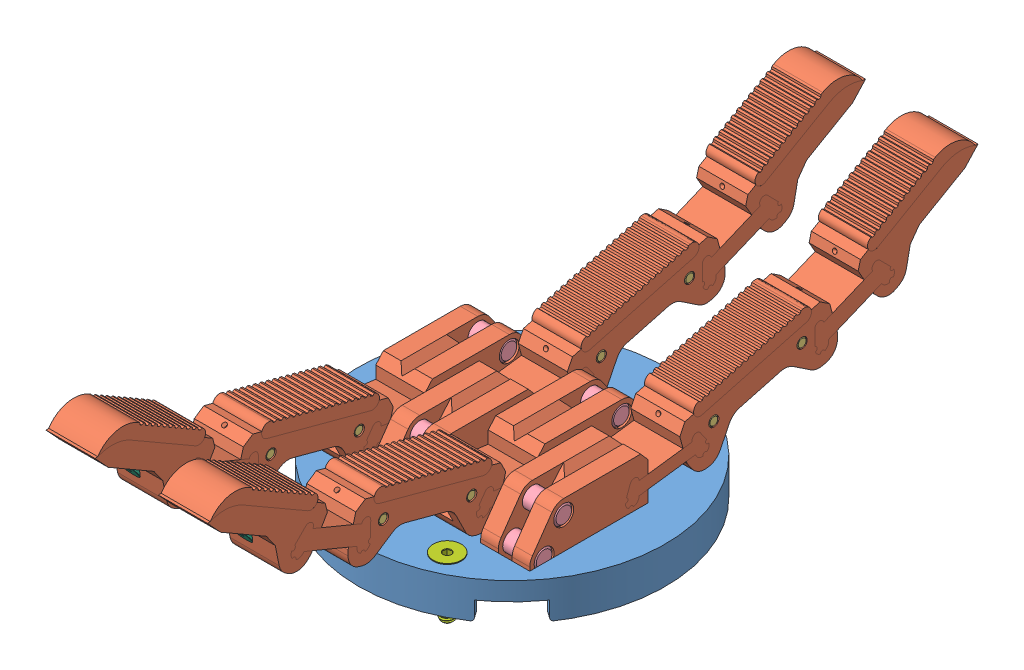
SolidWorks assembly block_top_ff_t, configuration Default. Lengths in mm.
Overall size (100 71.86 234.28).
37 component instances, 7 part files, 20 mates.
Components (placement in the parent):
- a1_f_t-1: a1_f_t [Default] at origin size (100 12.06 100)
- block_finger_ff_t-1: block_finger_ff_t [Default] at (-9.0917 8.2832 -0.0007) size (19 58.78 150.92)
  - finger_ff_t-1: finger_ff_t [Default] at origin size (19 58.78 150.92)
  - 98381A472 D1-8 L5-8-1: 98381A472 D1-8 L5-8 [98381A472] at (0.0625 5.5634 -30.2193) size (15.88 3.17 3.17)
  - 98381A472 D1-8 L5-8-2: 98381A472 D1-8 L5-8 [98381A472] at (0.0625 13.2775 -59.0086) size (15.88 3.17 3.17)
  - 98381A539 D1-4 L5-8-1: 98381A539 D1-4 L5-8 [98381A539] at (0.0625 3.5418 18.7031) size (15.88 6.35 6.35)
  - 98381A539 D1-4 L5-8-2: 98381A539 D1-4 L5-8 [98381A539] at (0.0625 -5.6082 25.11) size (15.88 6.35 6.35)
  - 93365A120 4-40 insert-1: 93365A120 4-40 insert [93365A120] at (0 25.5032 -95.7226) x (1 0 0) z (0 0.812659 -0.582739) size (4.37 3.82 4.37)
  - 91253A106 4-40 L1-4 countersunk-1: 91253A106 4-40 L1-4 countersunk [91253A106] at (0 24.2671 -97.4464) x (0.996599 0.066964 -0.048019) z (0 -0.582739 -0.812659) size (6.48 6.48 6.63)
- block_finger_ff_t-2: block_finger_ff_t [Default] at (27.575 8.2832 -0.0007) size (19 58.78 150.92)
  - finger_ff_t-1: finger_ff_t [Default] at origin size (19 58.78 150.92)
  - 98381A472 D1-8 L5-8-1: 98381A472 D1-8 L5-8 [98381A472] at (0.0625 5.5634 -30.2193) size (15.88 3.17 3.17)
  - 98381A472 D1-8 L5-8-2: 98381A472 D1-8 L5-8 [98381A472] at (0.0625 13.2775 -59.0086) size (15.88 3.17 3.17)
  - 98381A539 D1-4 L5-8-1: 98381A539 D1-4 L5-8 [98381A539] at (0.0625 3.5418 18.7031) size (15.88 6.35 6.35)
  - 98381A539 D1-4 L5-8-2: 98381A539 D1-4 L5-8 [98381A539] at (0.0625 -5.6082 25.11) size (15.88 6.35 6.35)
  - 93365A120 4-40 insert-1: 93365A120 4-40 insert [93365A120] at (0 25.5032 -95.7226) x (1 0 0) z (0 0.812659 -0.582739) size (4.37 3.82 4.37)
  - 91253A106 4-40 L1-4 countersunk-1: 91253A106 4-40 L1-4 countersunk [91253A106] at (0 24.2671 -97.4464) x (0.996599 0.066964 -0.048019) z (0 -0.582739 -0.812659) size (6.48 6.48 6.63)
- block_finger_ff_t-3: block_finger_ff_t [Default] at (-27.575 8.2832 0.0007) x (-1 0 0) z (0 0 -1) size (19 58.78 150.92)
  - finger_ff_t-1: finger_ff_t [Default] at origin size (19 58.78 150.92)
  - 98381A472 D1-8 L5-8-1: 98381A472 D1-8 L5-8 [98381A472] at (0.0625 5.5634 -30.2193) size (15.88 3.17 3.17)
  - 98381A472 D1-8 L5-8-2: 98381A472 D1-8 L5-8 [98381A472] at (0.0625 13.2775 -59.0086) size (15.88 3.17 3.17)
  - 98381A539 D1-4 L5-8-1: 98381A539 D1-4 L5-8 [98381A539] at (0.0625 3.5418 18.7031) size (15.88 6.35 6.35)
  - 98381A539 D1-4 L5-8-2: 98381A539 D1-4 L5-8 [98381A539] at (0.0625 -5.6082 25.11) size (15.88 6.35 6.35)
  - 93365A120 4-40 insert-1: 93365A120 4-40 insert [93365A120] at (0 25.5032 -95.7226) x (1 0 0) z (0 0.812659 -0.582739) size (4.37 3.82 4.37)
  - 91253A106 4-40 L1-4 countersunk-1: 91253A106 4-40 L1-4 countersunk [91253A106] at (0 24.2671 -97.4464) x (0.996599 0.066964 -0.048019) z (0 -0.582739 -0.812659) size (6.48 6.48 6.63)
- block_finger_ff_t-4: block_finger_ff_t [Default] at (9.0917 8.2832 0.0007) x (-1 0 0) z (0 0 -1) size (19 58.78 150.92)
  - finger_ff_t-1: finger_ff_t [Default] at origin size (19 58.78 150.92)
  - 98381A472 D1-8 L5-8-1: 98381A472 D1-8 L5-8 [98381A472] at (0.0625 5.5634 -30.2193) size (15.88 3.17 3.17)
  - 98381A472 D1-8 L5-8-2: 98381A472 D1-8 L5-8 [98381A472] at (0.0625 13.2775 -59.0086) size (15.88 3.17 3.17)
  - 98381A539 D1-4 L5-8-1: 98381A539 D1-4 L5-8 [98381A539] at (0.0625 3.5418 18.7031) size (15.88 6.35 6.35)
  - 98381A539 D1-4 L5-8-2: 98381A539 D1-4 L5-8 [98381A539] at (0.0625 -5.6082 25.11) size (15.88 6.35 6.35)
  - 93365A120 4-40 insert-1: 93365A120 4-40 insert [93365A120] at (0 25.5032 -95.7226) x (1 0 0) z (0 0.812659 -0.582739) size (4.37 3.82 4.37)
  - 91253A106 4-40 L1-4 countersunk-1: 91253A106 4-40 L1-4 countersunk [91253A106] at (0 24.2671 -97.4464) x (0.996599 0.066964 -0.048019) z (0 -0.582739 -0.812659) size (6.48 6.48 6.63)
- 92210A197 8-32 L3-4 countersunk-1: 92210A197 8-32 L3-4 countersunk [92210A197] at (17.0093 1.7845 38.128) x (-0.285144 0 -0.958485) z (0 1 0) size (9.12 9.12 19.5)
- 92210A197 8-32 L3-4 countersunk-2: 92210A197 8-32 L3-4 countersunk [92210A197] at (17.0093 1.7845 -38.128) x (1 0 0) z (0 1 0) size (9.12 9.12 19.5)
- 92210A197 8-32 L3-4 countersunk-3: 92210A197 8-32 L3-4 countersunk [92210A197] at (-17.0093 1.7845 38.128) x (1 0 0) z (0 1 0) size (9.12 9.12 19.5)
- 92210A197 8-32 L3-4 countersunk-4: 92210A197 8-32 L3-4 countersunk [92210A197] at (-17.0093 1.7845 -38.128) x (1 0 0) z (0 1 0) size (9.12 9.12 19.5)
Mates (geometry in assembly coordinates):
- Coincident1: coincident anti-aligned: plane of a1_f_t-1 through (-1.0917 1.5 29.7843) normal (-1 0 0); plane of block_finger_ff_t-1/finger_ff_t-1 through (-1.0917 8.2832 -0.0007) normal (1 0 0)
- Coincident2: coincident anti-aligned: plane of a1_f_t-1 through (-1.0917 1.5 29.7843) normal (0 0 -1); plane of block_finger_ff_t-1/finger_ff_t-1 through (-1.0917 16.5 29.7843) normal (0 0 1)
- Coincident3: coincident anti-aligned: plane of a1_f_t-1 through (0 -1.5 0) normal (0 -1 0); plane of block_finger_ff_t-1/finger_ff_t-1 through (-9.0917 -1.5 -0.0007) normal (0 1 0)
- Coincident4: coincident anti-aligned: plane of a1_f_t-1 through (35.575 1.5 29.7843) normal (-1 0 0); plane of block_finger_ff_t-2/finger_ff_t-1 through (35.575 8.2832 -0.0007) normal (1 0 0)
- Coincident5: coincident anti-aligned: plane of a1_f_t-1 through (0 -1.5 0) normal (0 -1 0); plane of block_finger_ff_t-2/finger_ff_t-1 through (27.575 -1.5 -0.0007) normal (0 1 0)
- Coincident6: coincident anti-aligned: plane of a1_f_t-1 through (35.575 1.5 29.7843) normal (0 0 -1); plane of block_finger_ff_t-2/finger_ff_t-1 through (35.575 16.5 29.7843) normal (0 0 1)
- Coincident7: coincident anti-aligned: plane of a1_f_t-1 through (1.0917 1.5 8.7858) normal (1 0 0); plane of block_finger_ff_t-4/finger_ff_t-1 through (1.0917 8.2832 0.0007) normal (-1 0 0)
- Coincident8: coincident anti-aligned: plane of a1_f_t-1 through (17.2417 1.5 -29.7843) normal (0 0 1); plane of block_finger_ff_t-4/finger_ff_t-1 through (1.0917 16.5 -29.7843) normal (0 0 -1)
- Coincident9: coincident anti-aligned: plane of a1_f_t-1 through (0 -1.5 0) normal (0 -1 0); plane of block_finger_ff_t-4/finger_ff_t-1 through (9.0917 -1.5 0.0007) normal (0 1 0)
- Coincident10: coincident anti-aligned: plane of a1_f_t-1 through (-35.575 1.5 8.7858) normal (1 0 0); plane of block_finger_ff_t-3/finger_ff_t-1 through (-35.575 8.2832 0.0007) normal (-1 0 0)
- Coincident11: coincident anti-aligned: plane of a1_f_t-1 through (-19.425 1.5 -29.7843) normal (0 0 1); plane of block_finger_ff_t-3/finger_ff_t-1 through (-35.575 16.5 -29.7843) normal (0 0 -1)
- Coincident12: coincident anti-aligned: plane of a1_f_t-1 through (0 -1.5 0) normal (0 -1 0); plane of block_finger_ff_t-3/finger_ff_t-1 through (-27.575 -1.5 0.0007) normal (0 1 0)
- Concentric1: concentric aligned: cylinder of a1_f_t-1 through (17.0093 1.5 38.128) axis (0 1 0) radius 2.2479; circle of 92210A197 8-32 L3-4 countersunk-1
- Coincident13: coincident aligned: cone of a1_f_t-1 through (17.0093 1.5 38.128) axis (0 -1 0); cone of 92210A197 8-32 L3-4 countersunk-1 through (17.0093 -1.0603 38.128) axis (0 -1 0)
- Concentric3: concentric aligned: cylinder of a1_f_t-1 through (17.0093 1.5 -38.128) axis (0 1 0) radius 2.2479; circle of 92210A197 8-32 L3-4 countersunk-2
- Coincident14: coincident aligned: cone of a1_f_t-1 through (17.0093 1.5 -38.128) axis (0 -1 0); cone of 92210A197 8-32 L3-4 countersunk-2 through (17.0093 -1.0603 -38.128) axis (0 -1 0)
- Concentric5: concentric aligned: cylinder of a1_f_t-1 through (-17.0093 1.5 -38.128) axis (0 1 0) radius 2.2479; circle of 92210A197 8-32 L3-4 countersunk-4
- Coincident15: coincident aligned: cone of a1_f_t-1 through (-17.0093 1.5 -38.128) axis (0 -1 0); cone of 92210A197 8-32 L3-4 countersunk-4 through (-17.0093 -1.0603 -38.128) axis (0 -1 0)
- Concentric7: concentric aligned: cylinder of a1_f_t-1 through (-17.0093 1.5 38.128) axis (0 1 0) radius 2.2479; circle of 92210A197 8-32 L3-4 countersunk-3
- Coincident16: coincident aligned: cone of a1_f_t-1 through (-17.0093 1.5 38.128) axis (0 -1 0); cone of 92210A197 8-32 L3-4 countersunk-3 through (-17.0093 -1.0603 38.128) axis (0 -1 0)
